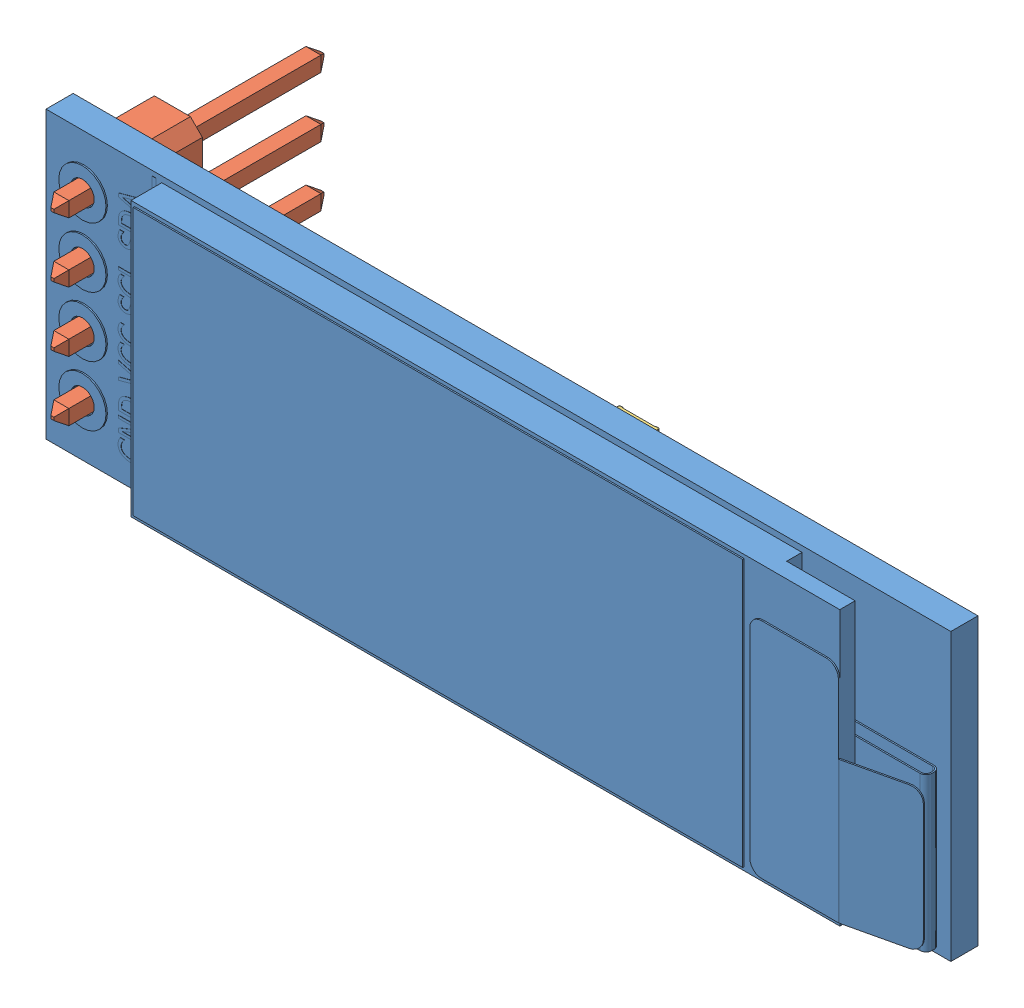
SolidWorks assembly OLED_0.91_128x32, configuration Predeterminado. Lengths in mm.
Overall size (38.3 12.1 11.46).
17 component instances, 4 part files, 0 mates.
Components (placement in the parent):
- OLED_0.91_128x32.stp-1: OLED_0.91_128x32.stp [Predeterminado] at origin size (38.3 12.1 11.46)
  - OLED_0.91_128x32.stp-1: OLED_0.91_128x32.stp [Predeterminado] at origin size (38.3 12.1 2.57)
  - Pin Header 4 x 1 TH 2.54mm Pitch.stp-1: Pin Header 4 x 1 TH 2.54mm Pitch.stp [Predeterminado] at (-17.55 -3.81 -2.6) size (2.54 10.16 11.43)
  - RESC-0603.stp-1: RESC-0603.stp [Predeterminado] at (4.3 -5.3 0) x (1 0 0) z (0 0 -1) size (1.7 0.9 0.55)
  - RESC-0603.stp-2: RESC-0603.stp [Predeterminado] at (4.3 -3.8 0) x (1 0 0) z (0 0 -1) size (1.7 0.9 0.55)
  - RESC-0603.stp-3: RESC-0603.stp [Predeterminado] at (4.3 -2.3 0) x (1 0 0) z (0 0 -1) size (1.7 0.9 0.55)
  - RESC-0603.stp-4: RESC-0603.stp [Predeterminado] at (4.3 -0.8 0) x (1 0 0) z (0 0 -1) size (1.7 0.9 0.55)
  - RESC-0603.stp-5: RESC-0603.stp [Predeterminado] at (4.3 0.7 0) x (1 0 0) z (0 0 -1) size (1.7 0.9 0.55)
  - RESC-0603.stp-6: RESC-0603.stp [Predeterminado] at (4.3 2.2 0) x (1 0 0) z (0 0 -1) size (1.7 0.9 0.55)
  - RESC-0603.stp-7: RESC-0603.stp [Predeterminado] at (4.3 3.7 0) x (1 0 0) z (0 0 -1) size (1.7 0.9 0.55)
  - RESC-0603.stp-8: RESC-0603.stp [Predeterminado] at (4.3 5.2 0) x (1 0 0) z (0 0 -1) size (1.7 0.9 0.55)
  - RESC-0603.stp-9: RESC-0603.stp [Predeterminado] at (-1.4 -3.06 0) x (1 0 0) z (0 0 -1) size (1.7 0.9 0.55)
  - RESC-0603.stp-10: RESC-0603.stp [Predeterminado] at (-1.4 -1.56 0) x (1 0 0) z (0 0 -1) size (1.7 0.9 0.55)
  - RESC-0603.stp-11: RESC-0603.stp [Predeterminado] at (-1.4 -0.06 0) x (1 0 0) z (0 0 -1) size (1.7 0.9 0.55)
  - RESC-0603.stp-12: RESC-0603.stp [Predeterminado] at (-1.4 1.44 0) x (1 0 0) z (0 0 -1) size (1.7 0.9 0.55)
  - RESC-0603.stp-13: RESC-0603.stp [Predeterminado] at (-1.4 2.94 0) x (1 0 0) z (0 0 -1) size (1.7 0.9 0.55)
  - 2SD0601A.stp-1: 2SD0601A.stp [Predeterminado] at (-9.8 -1.3 -0.08) x (1 0 0) z (0 1 0) size (2.76 1.18 2.9)
